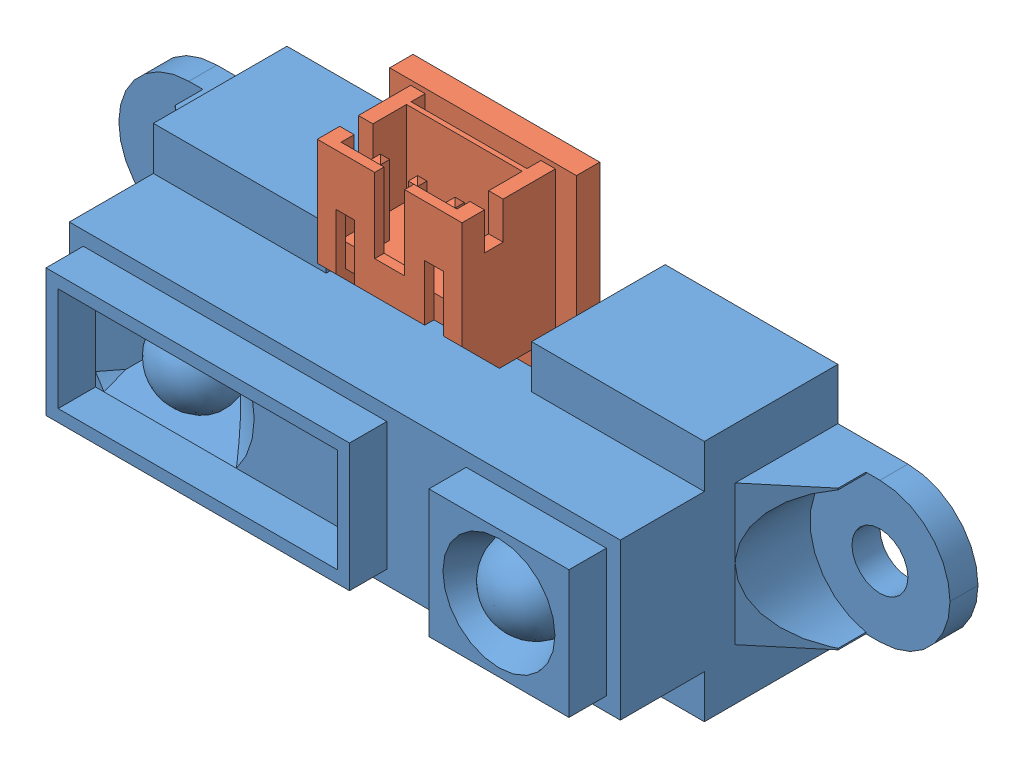
SolidWorks assembly Sharp IR GP2D120, configuration Predeterminado. Lengths in mm.
Overall size (44.5 19 13.9).
2 component instances, 2 part files, 3 mates.
Components (placement in the parent):
- Sharp IR Body-1: Sharp IR Body [Predeterminado] at (-3.237 2.158 -6.95) size (44.5 13 13.9)
- Sharp IR JST-1: Sharp IR JST [Predeterminado] at (-3.237 2.158 -3.95) size (28 18 7)
Mates (geometry in assembly coordinates):
- Distancia1: distance = 3 mm aligned: plane of Sharp IR JST-1 through (-3.237 -22.0657 -3.95) normal (0 0 -1); plane of Sharp IR Body-1 through (-17.987 8.658 -6.95) normal (0 0 -1)
- Coincidente3: coincident anti-aligned: plane of Sharp IR Body-1 through (-17.237 2.158 -0.95) normal (1 0 0); plane of Sharp IR JST-1 through (-17.237 -22.0657 -2.7) normal (-1 0 0)
- Distancia2: distance = 0.25 mm anti-aligned: plane of Sharp IR JST-1 through (-3.237 7.658 -2.7) normal (0 1 0); plane of Sharp IR Body-1 through (-28.4532 7.908 -0.95) normal (0 -1 0)
